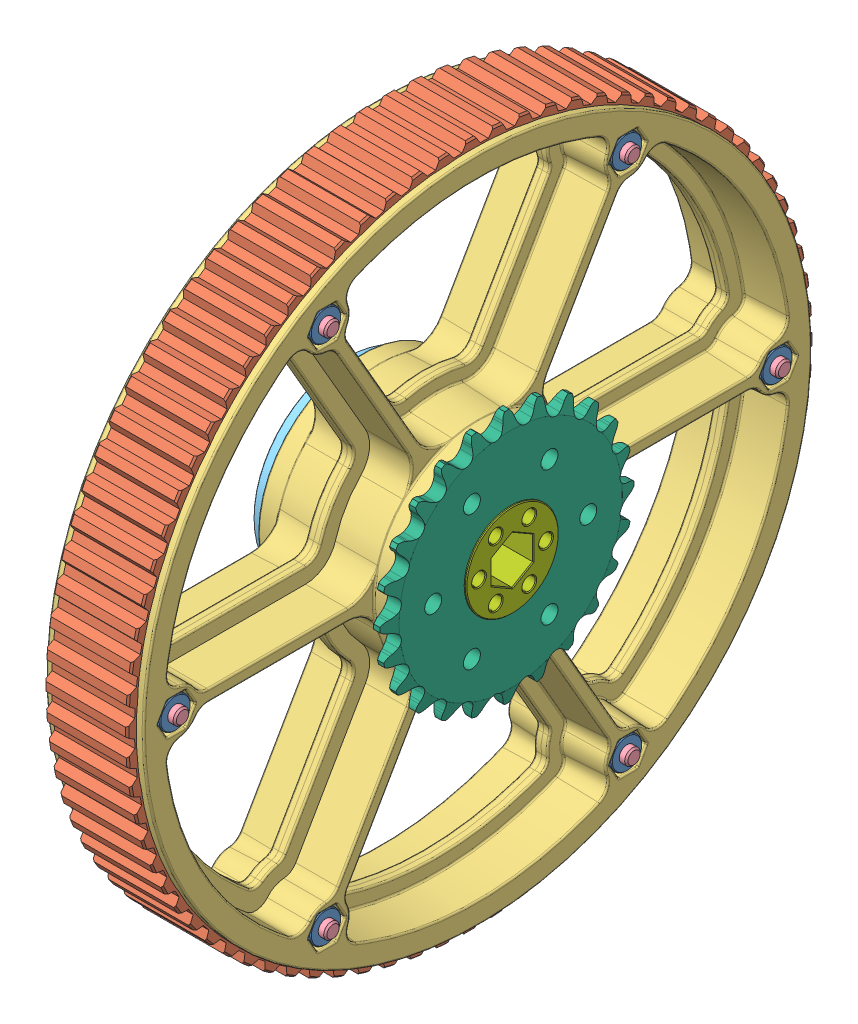
SolidWorks assembly Wheel Drive Fixed, configuration Default. Lengths in mm.
Overall size (51.94 234.45 234.45).
19 component instances, 7 part files, 9 mates.
Components (placement in the parent):
- 8PlactionRough-1: 8PlactionRough [Default] at origin size (41.66 234.45 234.45)
  - 10-32_nylock_nut-1: 10-32_nylock_nut [Default] at (125.0283 -70.4661 166.4862) x (0 0.793594 -0.608447) z (-1 0 0) size (11.98 11.69 7.5)
  - 10-32_nylock_nut-2: 10-32_nylock_nut [Default] at (125.0283 179.4143 -22.2176) x (0 -0.923728 -0.383049) z (-1 0 0) size (11.98 11.69 7.5)
  - 10-32_nylock_nut-3: 10-32_nylock_nut [Default] at (125.0283 70.4661 -166.4862) x (0 -0.793594 0.608447) z (-1 0 0) size (11.98 11.69 7.5)
  - 10-32_nylock_nut-4: 10-32_nylock_nut [Default] at (125.0283 -108.9482 -144.2686) x (0 0.130134 0.991496) z (-1 0 0) size (11.98 11.69 7.5)
  - 10-32_nylock_nut-5: 10-32_nylock_nut [Default] at (125.0283 -179.4143 22.2176) x (0 0.923728 0.383049) z (-1 0 0) size (11.98 11.69 7.5)
  - 10-32_nylock_nut-6: 10-32_nylock_nut [Default] at (125.0283 108.9482 144.2686) x (0 -0.130134 -0.991496) z (-1 0 0) size (11.98 11.69 7.5)
  - 8RoughTread-1: 8RoughTread [Default] at (8.128 0 0) x (0 -0.992815 0.119662) z (1 0 0) size (210.74 210.74 25.4)
  - 8MW_d01_v2-1: 8MW_d01_v2 [Default] at origin size (22.87 205.23 205.23)
  - 8MW_d01_v2-2: 8MW_d01_v2 [Default] at (41.656 0 0) x (-1 0 0) z (0 0 -1) size (22.87 205.23 205.23)
  - 10-32x1000_shcs-1: 10-32x1000_shcs [Default] at (7.4168 0 92.456) x (0 -0.961068 -0.276312) z (0 0.276312 -0.961068) size (7.82 30.18 7.82)
  - 10-32x1000_shcs-2: 10-32x1000_shcs [Default] at (7.4168 80.0692 -46.228) x (0 0.241241 0.970465) z (0 -0.970465 0.241241) size (7.82 30.18 7.82)
  - 10-32x1000_shcs-3: 10-32x1000_shcs [Default] at (7.4168 0 -92.456) x (0 0.961068 0.276312) z (0 -0.276312 0.961068) size (7.82 30.18 7.82)
  - 10-32x1000_shcs-4: 10-32x1000_shcs [Default] at (7.4168 -80.0692 -46.228) x (0 0.719827 -0.694154) z (0 0.694154 0.719827) size (7.82 30.18 7.82)
  - 10-32x1000_shcs-5: 10-32x1000_shcs [Default] at (7.4168 -80.0692 46.228) x (0 -0.241241 -0.970465) z (0 0.970465 -0.241241) size (7.82 30.18 7.82)
  - 10-32x1000_shcs-6: 10-32x1000_shcs [Default] at (7.4168 80.0692 46.228) x (0 -0.719827 0.694154) z (0 -0.694154 -0.719827) size (7.82 30.18 7.82)
- 500 Hex Hub (am-0096a)-3: 500 Hex Hub (am-0096a) [Default] at (13.9241 0 0) size (25.4 57.15 57.15)
- S35-24L Aluminum Sprocket (am-0217)-1: S35-24L Aluminum Sprocket (am-0217) [2299K314] at (43.7896 0 0) x (0 0.5 -0.866025) z (1 0 0) size (77.98 77.98 4.27)
- Hex Spacer 0.570 L x 0.5 ID Hex x 1.124 OD (am-1305)-4: Hex Spacer 0.570 L x 0.5 ID Hex x 1.124 OD (am-1305) [Default] at (46.482 0 0) x (0 1 0) z (-1 0 0) size (28.55 28.55 14.48)
Mates (geometry in assembly coordinates):
- Concentric2: concentric aligned: cone of 8PlactionRough-1/8MW_d01_v2-2 through (41.1657 0 0) axis (-1 0 0); cylinder of S35-24L Aluminum Sprocket (am-0217)-1 through (45.9232 0 0) axis (-1 0 0) radius 14.2812
- Concentric3: concentric anti-aligned: cone of 8PlactionRough-1/8MW_d01_v2-2 through (34.8069 20.6222 11.9062) axis (-1 0 0); cylinder of S35-24L Aluminum Sprocket (am-0217)-1 through (41.656 20.6222 11.9062) axis (1 0 0) radius 2.6162
- Coincident1: coincident anti-aligned: plane of 8PlactionRough-1/8MW_d01_v2-2 through (41.656 0 -31.75) normal (1 0 0); plane of S35-24L Aluminum Sprocket (am-0217)-1 through (41.656 -29.6785 -17.1349) normal (-1 0 0)
- Concentric4: concentric anti-aligned: cylinder of 8PlactionRough-1/8MW_d01_v2-1 through (-60 0 0) axis (1 0 0) radius 12.7; cylinder of 500 Hex Hub (am-0096a)-3 through (19.939 0 0) axis (-1 0 0) radius 12.1666
- Concentric5: concentric anti-aligned: cone of 8PlactionRough-1/8MW_d01_v2-1 through (6.8491 20.6222 11.9062) axis (1 0 0); cylinder of 500 Hex Hub (am-0096a)-3 through (-4.572 20.6222 11.9062) axis (-1 0 0) radius 2.5908
- Coincident2: coincident anti-aligned: plane of 8PlactionRough-1/8MW_d01_v2-1 through (0 0 31.75) normal (-1 0 0); plane of 500 Hex Hub (am-0096a)-3 through (0 28.575 0) normal (1 0 0)
- Concentric6: concentric anti-aligned: cylinder of 8PlactionRough-1/8MW_d01_v2-2 through (101.656 0 0) axis (-1 0 0) radius 12.7; cylinder of Hex Spacer 0.570 L x 0.5 ID Hex x 1.124 OD (am-1305)-4 through (32.004 0 0) axis (1 0 0) radius 14.2748
- Parallel1: parallel aligned: plane of 500 Hex Hub (am-0096a)-3 through (19.939 -7.3617 0) normal (0 0.866025 -0.5); plane of Hex Spacer 0.570 L x 0.5 ID Hex x 1.124 OD (am-1305)-4 through (32.004 -7.3323 0) normal (0 0.866025 -0.5)
- Coincident5: coincident anti-aligned: plane of 8PlactionRough-1/8MW_d01_v2-2 through (32.004 0 -14.2875) normal (1 0 0); plane of Hex Spacer 0.570 L x 0.5 ID Hex x 1.124 OD (am-1305)-4 through (32.004 0 0) normal (-1 0 0)
